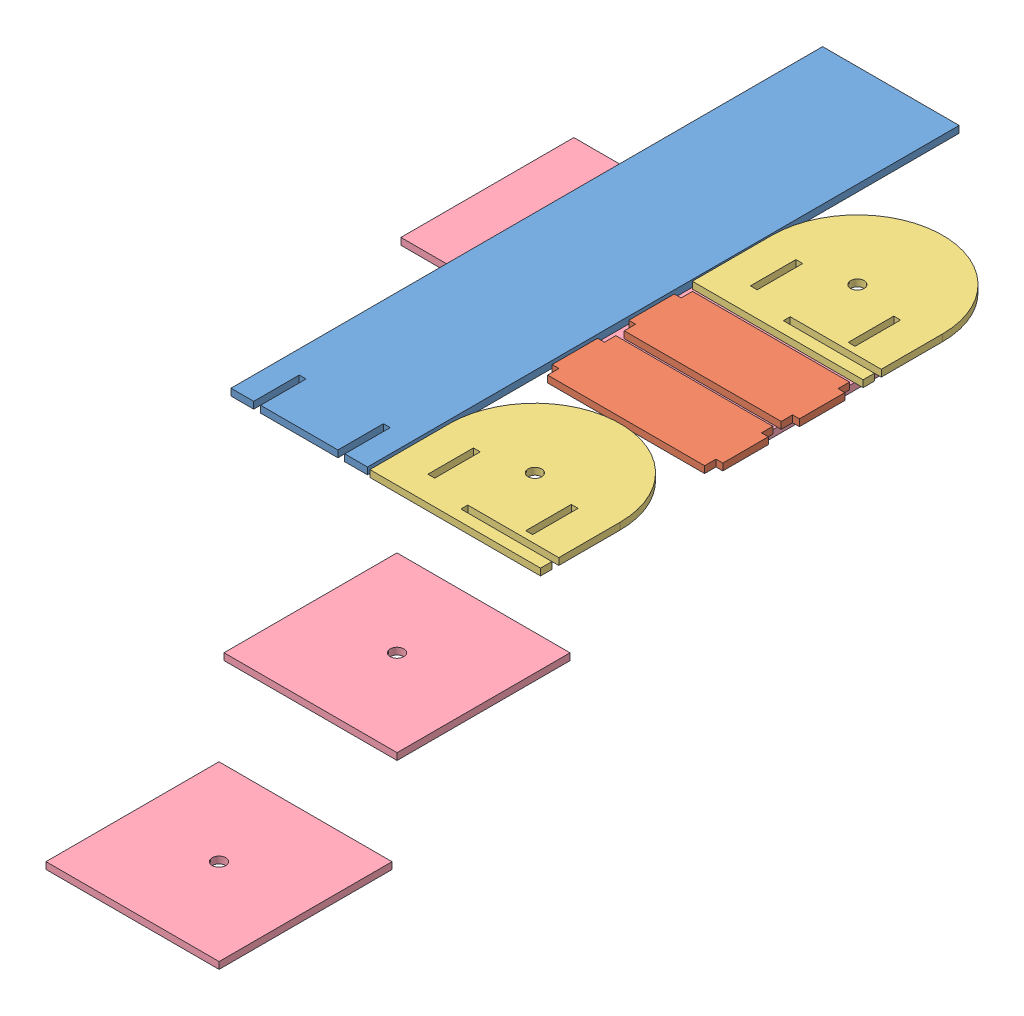
SolidWorks assembly Assem1, configuration Default. Lengths in mm.
Overall size (218.33 225.14 309.36).
9 component instances, 4 part files, 0 mates.
Components (placement in the parent):
- base-1: base [Default] at (-114.9822 73.5 139.0584) size (60 3 260)
- Attach-2: Attach [Default] at (-50.4137 73.5 64.4983) size (75 3 30)
- snkle-1: snkle [Default] at (-123.479 73.5 139.5079) size (75 3 72.5)
- snkle-2: snkle [Default] at (-122.7929 75 -1.5159) size (75 3 72.5)
- Attach-3: Attach [Default] at (-50.4183 73.5 30.8111) size (75 3 30)
- hole joint-2: hole joint [Default] at (-158.0638 -144.1389 101.2308) x (1 0 0) z (0 -1 0) size (76.05 76 3)
- hole joint-3: hole joint [Default] at (-158.0935 -103.7869 22.9728) x (1 0 0) z (0 -1 0) size (76.05 76 3)
- hole joint-4: hole joint [Default] at (-157.8931 15.6028 -54.5573) x (1 0 0) z (0 -1 0) size (76.05 76 3)
- hole joint-5: hole joint [Default] at (-157.7966 -63.1823 -131.826) x (0 0 1) z (0 -1 0) size (76.05 76 3)
